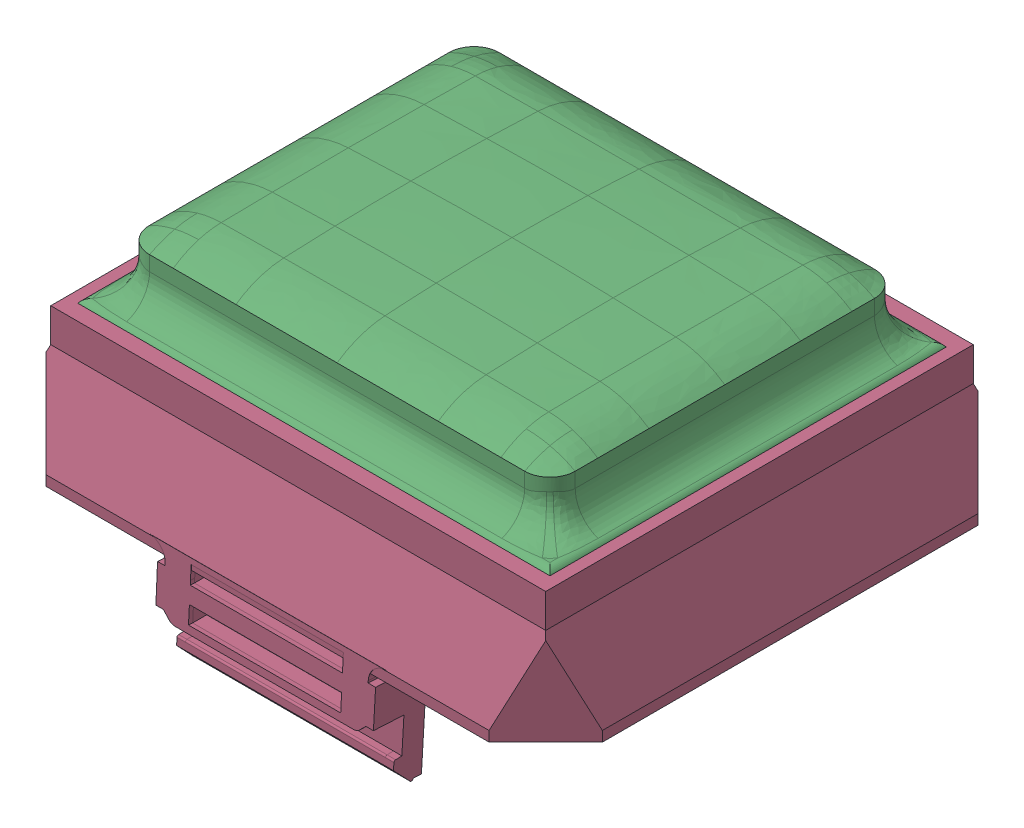
SolidWorks assembly SingleDot, configuration 默认. Lengths in mm.
Overall size (33 18.27 29.5).
5 component instances, 5 part files, 18 mates.
Components (placement in the parent):
- Lens-1: Lens [默认] at origin size (28.33 2.18 23.83)
- InsideSkin-1: InsideSkin [默认] at (0.0001 0 0.2499) size (23.8 5.48 19.29)
- Topskin-1: Topskin [默认] at (0.0001 2 0.2499) size (28.02 6.25 23.52)
- Supportbase-2: Supportbase [默认] at origin size (33 14.02 29.5)
- Dor-1: Dor [默认] at (-1.2499 23.9 -0.9614) x (-1 0 0) z (0 -1 0) size (18.98 16.99 1.63)
Mates (geometry in assembly coordinates):
- 同心2: concentric anti-aligned: cylinder of InsideSkin-1 through (10.8751 17.7531 8.6249) axis (0 1 0) radius 0.7; cylinder of Board3Con1612611OriginalSkin_TOP-1 through (10.8751 24 8.6249) axis (0 -1 0) radius 0.7
- 同心3: concentric anti-aligned: cylinder of InsideSkin-1 through (10.8751 17.7531 -9.1251) axis (0 1 0) radius 0.7; cylinder of Board3Con1612611OriginalSkin_TOP-1 through (10.8751 24 -9.1251) axis (0 -1 0) radius 0.7
- 重合4: coincident aligned: plane of InsideSkin-1 through (10.8751 19 -9.1251) normal (0 -1 0); plane of Board3Con1612611OriginalSkin_TOP-1 through (0.0001 19 0.2499) normal (0 -1 0)
- 重合6: coordinate: point of NewContiSupportBase-2
- 重合7: coincident anti-aligned: plane of lensall-1 through (13.75 19 -11.5) normal (0.939693 0.34202 0); plane of NewContiSupportBase-2 through (13.75 19 12.7803) normal (-0.939693 -0.34202 0)
- 同心5: concentric aligned: cylinder of lensall-1 through (13.3294 18.6938 -11.0794) axis (-0.323616 0.889126 0.323616) radius 0.5; cylinder of NewContiSupportBase-2 through (10.7866 25.6801 -8.5366) axis (-0.323616 0.889126 0.323616) radius 0.5
- 重合8: coincident anti-aligned: plane of lensall-1 through (0 18 0) normal (0 -1 0); plane of NewContiSupportBase-2 through (0 18 0) normal (0 1 0)
- 重合9: coincident anti-aligned: plane of lensall-1 through (0 19 0) normal (0 1 0); plane of Board3Con1612611OriginalSkin_TOP-1 through (0.0001 19 0.2499) normal (0 -1 0)
- 重合10: coincident anti-aligned: plane of Board3Con1612611OriginalSkin_TOP-1 through (0.0001 19 11.7499) normal (0 0 1); plane of NewContiSupportBase-2 through (-13.5999 21 11.7499) normal (0 0 -1)
- 重合11: coincident anti-aligned: plane of Board3Con1612611OriginalSkin_TOP-1 through (14.0001 19 0.2499) normal (1 0 0); plane of NewContiSupportBase-2 through (14.0001 21 11.7499) normal (-1 0 0)
- 平行1: parallel: plane of InsideSkin-1 through (-11.3749 17.7531 9.3249) normal (0 0 1); line of Dor-1 through (8.7251 23.9 6.9749) axis (-1 0 0)
- 平行2: parallel: plane of InsideSkin-1 through (-12.0749 17.7531 -9.1251) normal (-1 0 0); line of Dor-1 through (-12.2749 23.9 -8.0251) axis (0 0 1)
- 距离1: distance = 1.8 mm: line of Dor-1 through (8.7251 23.9 -8.0251) axis (-1 0 0); plane of InsideSkin-1 through (-11.3749 17.7531 -9.8251) normal (0 0 -1)
- 平行3: parallel anti-aligned: line of Supportbase-2 through (14.6801 19 12.1801) axis (0 0 -1); line of Dor-1 through (9.9597 23.9 -9.2955) axis (0 0 1)
- 距离2: distance = 5 mm: plane of Lens-1 through (0 19 0) normal (0 1 0); line of Dor-1 through (-10.7499 26.3155 -7.7501) axis (0 0 1)
- 距离3: distance = 2.85 mm: plane of InsideSkin-1 through (11.5751 17.7531 -9.1251) normal (1 0 0); line of Dor-1 through (8.7251 23.9 -8.0251) axis (0 0 1)
- 平行4: parallel aligned: line of Supportbase-2 through (14.1801 19 -12.6801) axis (-1 0 0); line of Dor-1 through (9.9597 23.9 10.7045) axis (-1 0 0)
- 距离5: distance = 4.9 mm: plane of Lens-1 through (0 19 0) normal (0 1 0); line of Dor-1 through (8.7251 23.9 -8.0251) axis (0 0 1)
